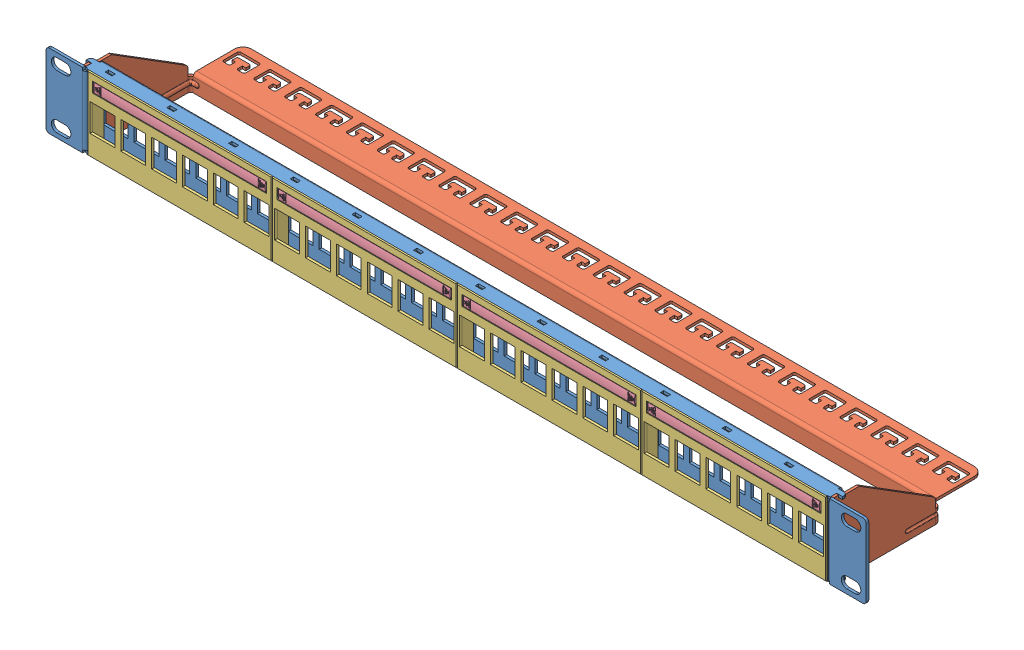
SolidWorks assembly Keystone-Pannel, configuration Standard. Lengths in mm.
Overall size (482.6 43.7 92.75).
14 component instances, 4 part files, 18 mates.
Components (placement in the parent):
- 19-Keystone-Pannel-Front-1: 19-Keystone-Pannel-Front [Standard] at (-241.3 -21.8 -9.9) size (482.6 43.6 9.9)
- 19-Keystone-Pannel-Back-1: 19-Keystone-Pannel-Back [Standard] at (-241.3 -21.7 -64.5) size (442.58 43.6 90.8)
- Keystone-Pannel-6-Module-1: Keystone-Pannel-6-Module [Standard] at (-349.7 0 0) size (108.7 43.6 8.85)
  - 19-Keystone-Pannel-Einsatz-1: 19-Keystone-Pannel-Einsatz [Standard] at (-54.35 -21.8 -8.4) size (108.7 43.6 8.4)
  - 19-Keystone-Pannel-Glas-1: 19-Keystone-Pannel-Glas [Standard] at (-54.1 -7 -1) size (104 5.8 1.45)
- Keystone-Pannel-6-Module-2: Keystone-Pannel-6-Module [Standard] at (-241 0 0) size (108.7 43.6 8.85)
  - 19-Keystone-Pannel-Einsatz-1: 19-Keystone-Pannel-Einsatz [Standard] at (-54.35 -21.8 -8.4) size (108.7 43.6 8.4)
  - 19-Keystone-Pannel-Glas-1: 19-Keystone-Pannel-Glas [Standard] at (-54.1 -7 -1) size (104 5.8 1.45)
- Keystone-Pannel-6-Module-3: Keystone-Pannel-6-Module [Standard] at (-132.3 0 0) size (108.7 43.6 8.85)
  - 19-Keystone-Pannel-Einsatz-1: 19-Keystone-Pannel-Einsatz [Standard] at (-54.35 -21.8 -8.4) size (108.7 43.6 8.4)
  - 19-Keystone-Pannel-Glas-1: 19-Keystone-Pannel-Glas [Standard] at (-54.1 -7 -1) size (104 5.8 1.45)
- Keystone-Pannel-6-Module-4: Keystone-Pannel-6-Module [Standard] at (-23.6 0 0) size (108.7 43.6 8.85)
  - 19-Keystone-Pannel-Einsatz-1: 19-Keystone-Pannel-Einsatz [Standard] at (-54.35 -21.8 -8.4) size (108.7 43.6 8.4)
  - 19-Keystone-Pannel-Glas-1: 19-Keystone-Pannel-Glas [Standard] at (-54.1 -7 -1) size (104 5.8 1.45)
Mates (geometry in assembly coordinates):
- Deckungsgleich1: coincident aligned: plane of 19-Keystone-Pannel-Front-1 through (-234.2558 -21.8 0) normal (0 0 1); plane of assembly
- Deckungsgleich2: coincident aligned: plane of 19-Keystone-Pannel-Front-1 through (-241.3 0 -29.7363) normal (0 1 0); plane of assembly
- Deckungsgleich3: coincident aligned: plane of 19-Keystone-Pannel-Front-1 through (0 0 -1.5) normal (1 0 0); plane of assembly
- Deckungsgleich4: coincident anti-aligned: plane of 19-Keystone-Pannel-Front-1 through (-234.2558 -21.8 -1.5) normal (0 0 -1); plane of 19-Keystone-Pannel-Back-1 through (-460.5 0.1 -1.5) normal (0 0 1)
- Deckungsgleich5: coincident anti-aligned: plane of 19-Keystone-Pannel-Front-1 through (-460.5 -1.5 -1.5) normal (-1 0 0); plane of 19-Keystone-Pannel-Back-1 through (-460.5 -21.7 -33.1965) normal (1 0 0)
- Deckungsgleich6: coincident anti-aligned: plane of 19-Keystone-Pannel-Front-1 through (-241.3 -1.5 -29.7363) normal (0 -1 0); plane of 19-Keystone-Pannel-Back-1 through (-462 -1.5 -4.4) normal (0 1 0)
- Deckungsgleich7: coincident: plane of 19-Keystone-Pannel-Front-1 through (-241.3 -42.1 -29.7363) normal (0 1 0); plane of Keystone-Pannel-6-Module-1/19-Keystone-Pannel-Einsatz-1 through (-404.05 -39.0012 -5.5475) normal (0 -1 0)
- Deckungsgleich8: coincident: plane of 19-Keystone-Pannel-Front-1 through (-241.3 -42.1 -29.7363) normal (0 1 0); plane of Keystone-Pannel-6-Module-2/19-Keystone-Pannel-Einsatz-1 through (-295.35 -43.0123 -6.8685) normal (0 -1 0)
- Deckungsgleich9: coincident: plane of 19-Keystone-Pannel-Front-1 through (-241.3 -42.1 -29.7363) normal (0 1 0); plane of Keystone-Pannel-6-Module-3/19-Keystone-Pannel-Einsatz-1 through (-236.7698 -37.9789 -4.861) normal (0 -1 0)
- Deckungsgleich10: coincident: plane of 19-Keystone-Pannel-Front-1 through (-241.3 -42.1 -29.7363) normal (0 1 0); plane of Keystone-Pannel-6-Module-4/19-Keystone-Pannel-Einsatz-1 through (-120.6201 -42.1 -4.45) normal (0 -1 0)
- Deckungsgleich11: coincident: plane of 19-Keystone-Pannel-Front-1 through (-241.3 -21.8 -8.4) normal (0 0 1); plane of Keystone-Pannel-6-Module-4/19-Keystone-Pannel-Einsatz-1 through (-120.6201 -21.8 -8.4) normal (0 0 -1)
- Deckungsgleich13: coincident: plane of 19-Keystone-Pannel-Front-1 through (-241.3 -21.8 -8.4) normal (0 0 1); plane of Keystone-Pannel-6-Module-3/19-Keystone-Pannel-Einsatz-1 through (-186.65 -21.8 -8.4) normal (0 0 -1)
- Deckungsgleich14: coincident: plane of 19-Keystone-Pannel-Front-1 through (-241.3 -21.8 -8.4) normal (0 0 1); plane of Keystone-Pannel-6-Module-2/19-Keystone-Pannel-Einsatz-1 through (-295.35 -21.8 -8.4) normal (0 0 -1)
- Deckungsgleich15: coincident: plane of 19-Keystone-Pannel-Front-1 through (-241.3 -21.8 -8.4) normal (0 0 1); plane of Keystone-Pannel-6-Module-1/19-Keystone-Pannel-Einsatz-1 through (-404.05 -21.8 -8.4) normal (0 0 -1)
- Deckungsgleich16: coincident anti-aligned: plane of 19-Keystone-Pannel-Front-1 through (-23.6 -21.8 -226.9221) normal (-1 0 0); plane of Keystone-Pannel-6-Module-4/19-Keystone-Pannel-Einsatz-1 through (-23.6 -43.6 -8.4) normal (1 0 0)
- Deckungsgleich17: coincident anti-aligned: plane of Keystone-Pannel-6-Module-3/19-Keystone-Pannel-Einsatz-1 through (-132.3 -43.6 -8.4) normal (1 0 0); plane of Keystone-Pannel-6-Module-4/19-Keystone-Pannel-Einsatz-1 through (-132.3 0 -8.4) normal (-1 0 0)
- Deckungsgleich18: coincident anti-aligned: plane of Keystone-Pannel-6-Module-2/19-Keystone-Pannel-Einsatz-1 through (-241 -43.6 -8.4) normal (1 0 0); plane of Keystone-Pannel-6-Module-3/19-Keystone-Pannel-Einsatz-1 through (-241 0 -8.4) normal (-1 0 0)
- Deckungsgleich19: coincident anti-aligned: plane of Keystone-Pannel-6-Module-1/19-Keystone-Pannel-Einsatz-1 through (-349.7 -43.6 -8.4) normal (1 0 0); plane of Keystone-Pannel-6-Module-2/19-Keystone-Pannel-Einsatz-1 through (-349.7 0 -8.4) normal (-1 0 0)
